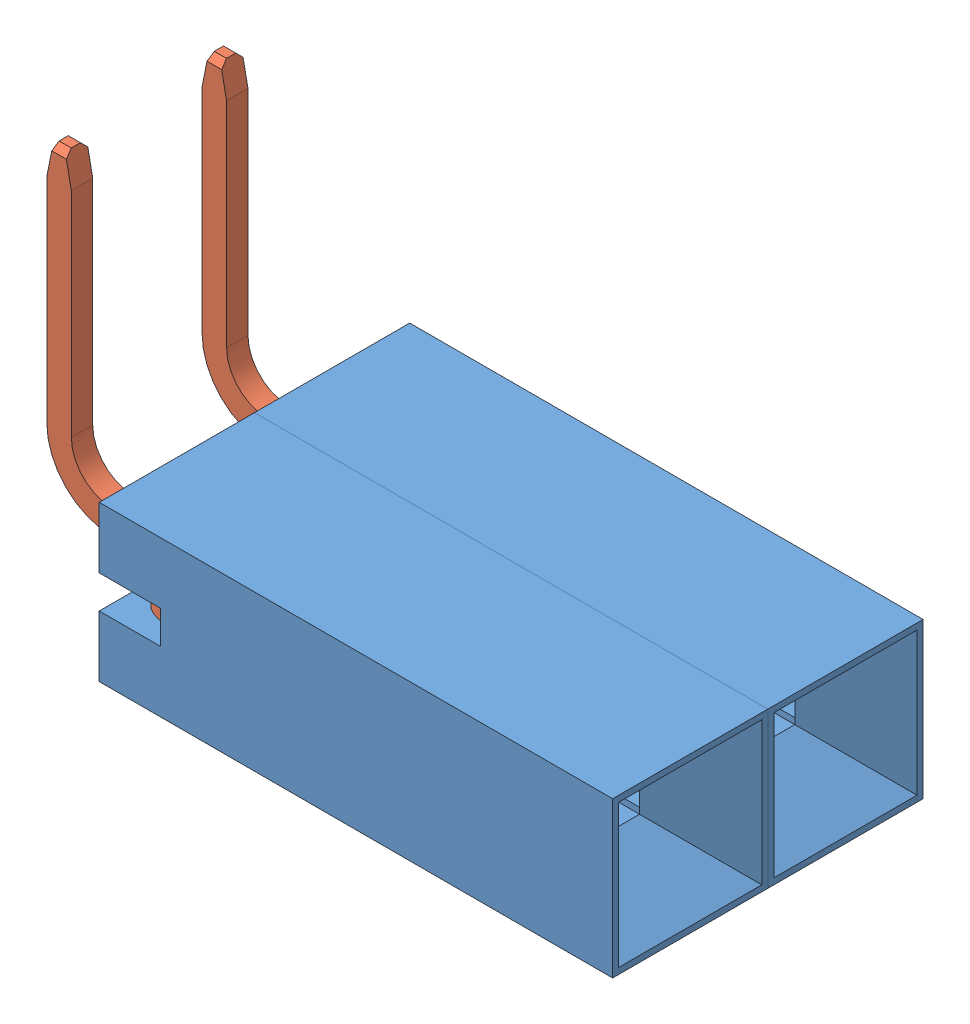
SolidWorks assembly H254_90deg_2pin, configuration Default. Lengths in mm.
Overall size (10.36 6.14 5.08).
6 component instances, 2 part files, 2 mates.
Components (placement in the parent):
- FrameAndPin_H254_90deg-1: FrameAndPin_H254_90deg [Default] at origin size (10.36 6.14 2.54)
  - frame_H254-1: frame_H254 [Default] at origin size (8.4 2.54 2.54)
  - pin-90deg-1: pin-90deg [Default] at (-0.0461 1.2682 1.27) x (0 0 -1) z (0.999998 -0.002105 0) size (1.95 5.07 7.58)
- FrameAndPin_H254_90deg-2: FrameAndPin_H254_90deg [Default] at (0 0 -2.54) size (10.36 6.14 2.54)
  - frame_H254-1: frame_H254 [Default] at origin size (8.4 2.54 2.54)
  - pin-90deg-1: pin-90deg [Default] at (-0.0461 1.2682 1.27) x (0 0 -1) z (0.999998 -0.002105 0) size (1.95 5.07 7.58)
Mates (geometry in assembly coordinates):
- Coincident1: coincident aligned: line of FrameAndPin_H254_90deg-1/frame_H254-1 through (8.4 8.4 2.54) axis (0 -1 0); line of FrameAndPin_H254_90deg-2/frame_H254-1 through (8.4 8.4 2.54) axis (0 -1 0)
- Coincident2: coincident aligned: line of FrameAndPin_H254_90deg-1/frame_H254-1 through (2.54 8.4 0) axis (0 0 1); line of FrameAndPin_H254_90deg-2/frame_H254-1 through (2.54 8.4 0) axis (0 0 1)
